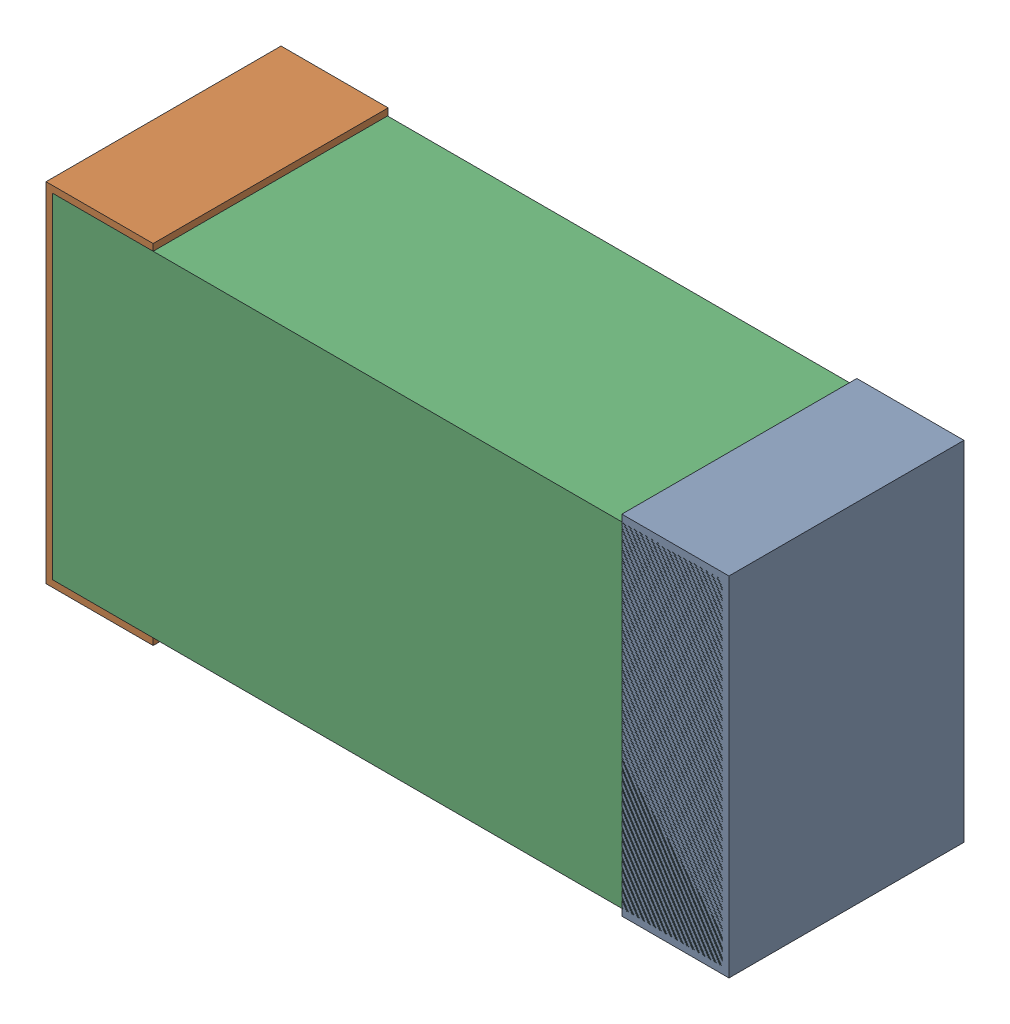
SolidWorks assembly C39, configuration Default. Lengths in mm.
Overall size (1.02 0.52 0.35).
6 component instances, 2 part files, 0 mates.
Components (placement in the parent):
- 870940480-1: 870940480 [Default] at (39.673 40.1066 -1.9516) size (0.16 0.52 0.35)
  - Extruded-1: Extruded [Default] at origin size (0.16 0.52 0.35)
- 870940480-2: 870940480 [Default] at (38.813 40.1066 -1.9516) size (0.16 0.52 0.35)
  - Extruded-1: Extruded [Default] at origin size (0.16 0.52 0.35)
- 870940640-1: 870940640 [Default] at (39.243 40.1066 -1.9506) size (1 0.5 0.35)
  - Extruded_2-1: Extruded_2 [Default] at origin size (1 0.5 0.35)
